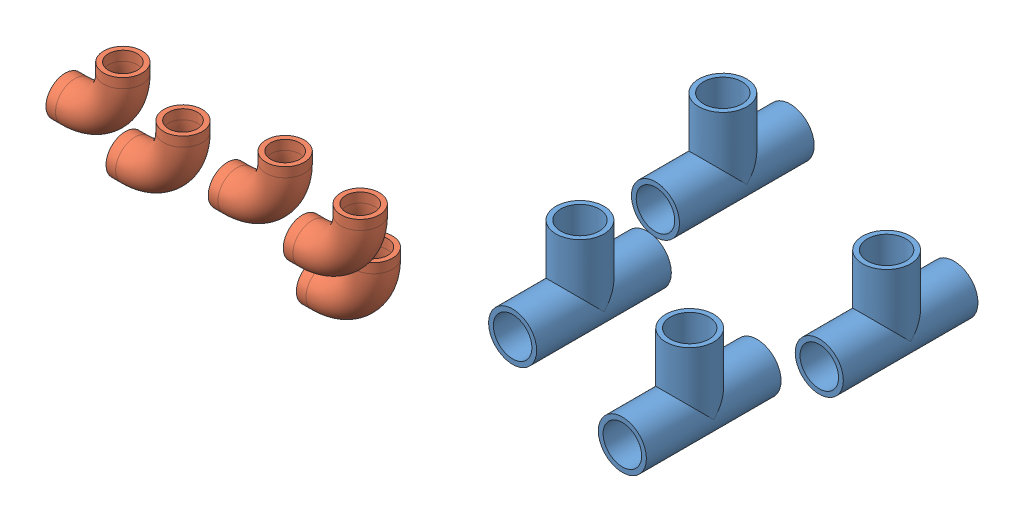
SolidWorks assembly Assem1, configuration Default. Lengths in mm.
Overall size (296.74 226.78 368.23).
9 component instances, 2 part files, 0 mates.
Components (placement in the parent):
- three_quarter_t-joint-1: three_quarter_t-joint [Default] at (46.1305 37.0306 58.061) size (31.75 60.33 88.9)
- three_quarter_elbow_joint-1: three_quarter_elbow_joint [Default] at (-38.6081 23.9487 242.1319) size (50.8 50.8 25.4)
- three_quarter_t-joint-2: three_quarter_t-joint [Default] at (60.2214 25.5299 166.4488) size (31.75 60.33 88.9)
- three_quarter_elbow_joint-2: three_quarter_elbow_joint [Default] at (-89.0436 161.9714 357.01) size (50.8 50.8 25.4)
- three_quarter_elbow_joint-3: three_quarter_elbow_joint [Default] at (28.5157 120.1478 317.9081) size (50.8 50.8 25.4)
- three_quarter_elbow_joint-4: three_quarter_elbow_joint [Default] at (-22.6766 123.8319 316.2605) size (50.8 50.8 25.4)
- three_quarter_elbow_joint-5: three_quarter_elbow_joint [Default] at (-138.7272 59.0191 267.664) size (50.8 50.8 25.4)
- three_quarter_t-joint-3: three_quarter_t-joint [Default] at (127.3197 -5.3477 161.1043) size (31.75 60.33 88.9)
- three_quarter_t-joint-4: three_quarter_t-joint [Default] at (142.1356 -10.8353 45.9304) size (31.75 60.33 88.9)
